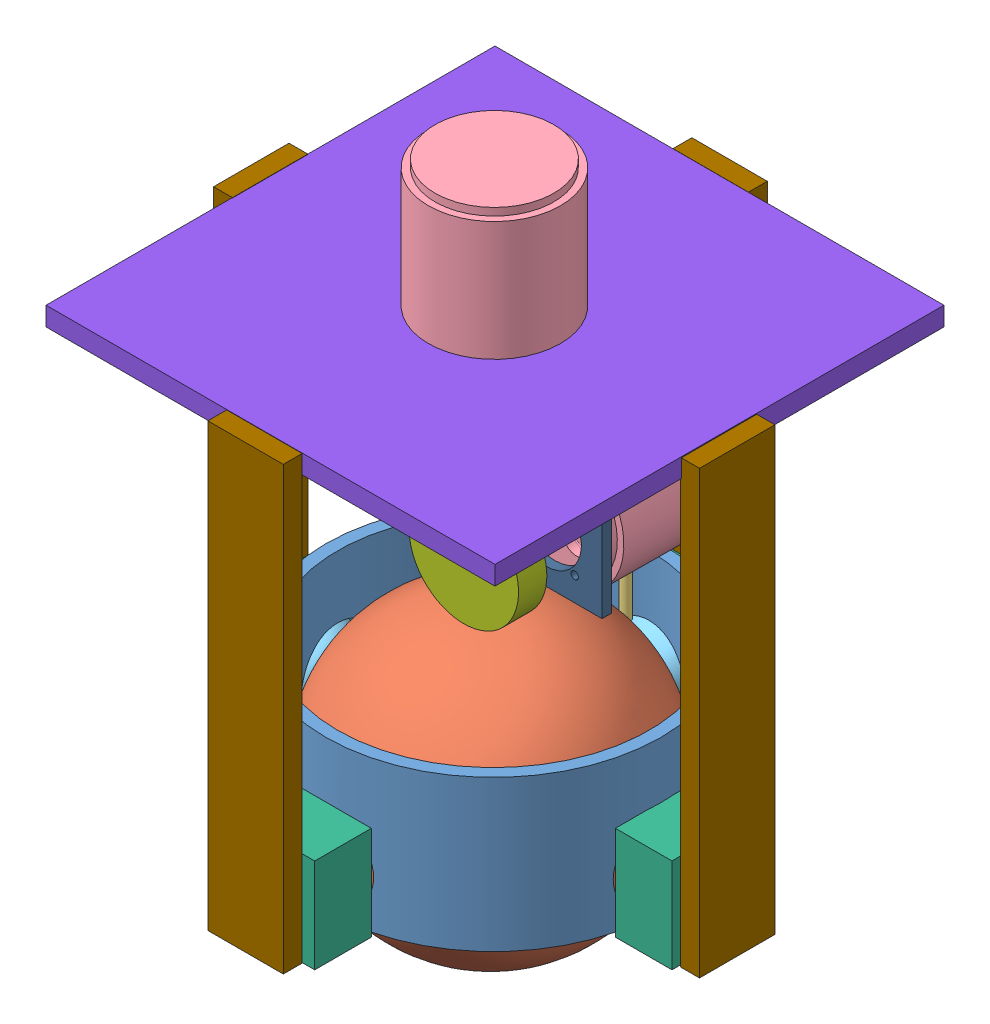
SolidWorks assembly BASEFRAME, configuration Default. Lengths in mm.
Overall size (257.45 356.79 258.39).
26 component instances, 11 part files, 0 mates.
Components (placement in the parent):
- Part3^BASEFRAME-1: Part3^BASEFRAME [Default] at origin (virtual)
- Ring-2: Ring [Default] at (58.3969 69.4206 130.1186) size (177.8 80 177.8)
- Ball-2: Ball [Default] at (57.0534 90.2408 130.2525) size (152.72 152.4 152.72)
- ringsupport-2: ringsupport [Default] at (141.6171 118.3743 137.934) size (5 30 5)
- ringsupport-4: ringsupport [Default] at (52.9689 119.0363 54.4711) size (5 30 5)
- motormodel-1: motormodel [Default] at (58.9938 370.8329 130.1733) x (0 -1 0) z (-0.765805 0 0.643073) size (103 70 70)
- motormodel-2: motormodel [Default] at (59.1428 193.9149 27.9507) x (-0.007304 0.000852 0.999973) z (-0.340585 -0.940212 -0.001686) size (103 70 70)
- BearingContainerAsm-1: BearingContainerAsm [Default] at (200.2621 159.2779 99.9799) x (0 -1 0) z (-1 0 0) size (50 50 43.6)
  - miniball-2: miniball [Default] at (64.8074 29.1677 66.8602) size (40 40 40)
  - container-3: container [Default] at (97.5898 25.7275 23.2563) x (-1 0 0) z (0 0 -1) size (50 50 30)
- BearingContainerAsm-2: BearingContainerAsm [Default] at (122.5889 65.8759 272.5177) x (-1 0 0) z (0 0 -1) size (50 50 43.6)
  - miniball-2: miniball [Default] at (64.8074 29.1677 66.8602) size (40 40 40)
  - container-3: container [Default] at (97.5898 25.7275 23.2563) x (-1 0 0) z (0 0 -1) size (50 50 30)
- BearingContainerAsm-3: BearingContainerAsm [Default] at (-9.061 65.5508 -12.1837) size (50 50 43.6)
  - miniball-2: miniball [Default] at (64.8074 29.1677 66.8602) size (40 40 40)
  - container-3: container [Default] at (97.5898 25.7275 23.2563) x (-1 0 0) z (0 0 -1) size (50 50 30)
- BearingContainerAsm-4: BearingContainerAsm [Default] at (-82.9992 65.5276 196.0263) x (0 0 -1) z (1 0 0) size (50 50 43.6)
  - miniball-2: miniball [Default] at (64.8074 29.1677 66.8602) size (40 40 40)
  - container-3: container [Default] at (97.5898 25.7275 23.2563) x (-1 0 0) z (0 0 -1) size (50 50 30)
- wheeeeel-1: wheeeeel [Default] at (58.5775 194.1439 130.9989) size (58 58 15)
- topsquare-1: topsquare [Default] at (59.0143 293.5564 129.9009) size (238 10 238)
- woodbarsupport-1: woodbarsupport [Default] at (56.1528 69.7336 254.2717) size (40 234 10)
- woodbarsupport-2: woodbarsupport [Default] at (54.3486 69.6091 5.8788) size (40 234 10)
- woodbarsupport-4: woodbarsupport [Default] at (-64.8069 69.7249 130.2853) x (0 0 -1) z (1 0 0) size (40 234 10)
- woodbarsupport-5: woodbarsupport [Default] at (182.6422 69.0903 130.1157) x (0 0 -1) z (1 0 0) size (40 234 10)
- lbrac_v2-1: lbrac_v2 [Default] at (92.1526 218.9234 140.8407) size (60 106.6 60)
